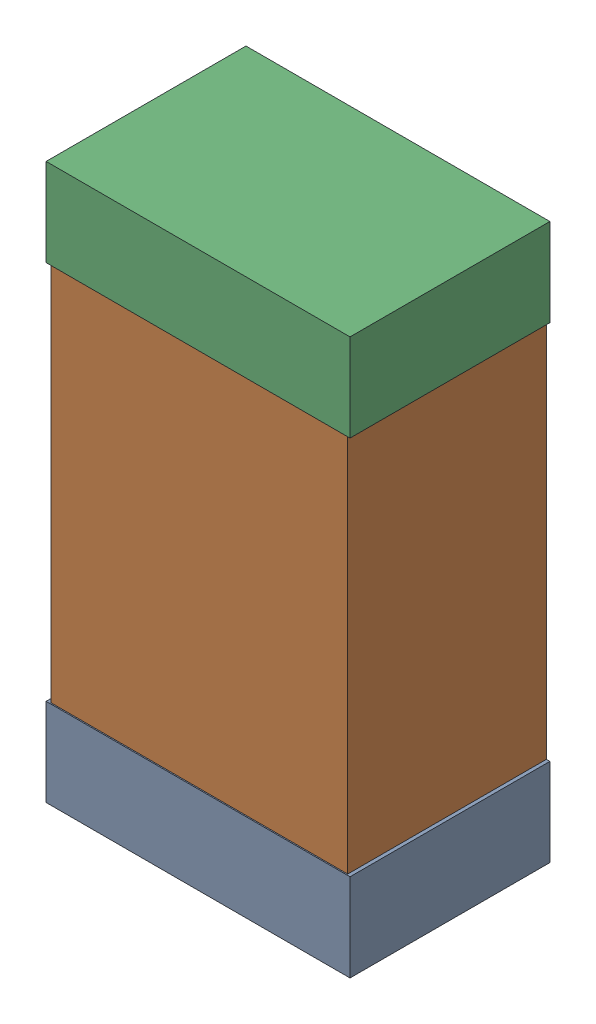
SolidWorks assembly 10uFKanaloa_v2.0.0_Power, configuration Default. Lengths in mm.
Overall size (1.3 2.38 0.85).
6 component instances, 2 part files, 0 mates.
Components (placement in the parent):
- 330415056-1: 330415056 [Default] at (131.6468 97.1944 0) size (1.3 0.38 0.85)
  - Extruded_2-1: Extruded_2 [Default] at origin size (1.3 0.38 0.85)
- 334787376-1: 334787376 [Default] at (131.6468 98.1944 0) size (1.27 2.2 0.85)
  - Extruded_16-1: Extruded_16 [Default] at origin size (1.27 2.2 0.85)
- 330415056-2: 330415056 [Default] at (131.6468 99.1944 0) size (1.3 0.38 0.85)
  - Extruded_2-1: Extruded_2 [Default] at origin size (1.3 0.38 0.85)
